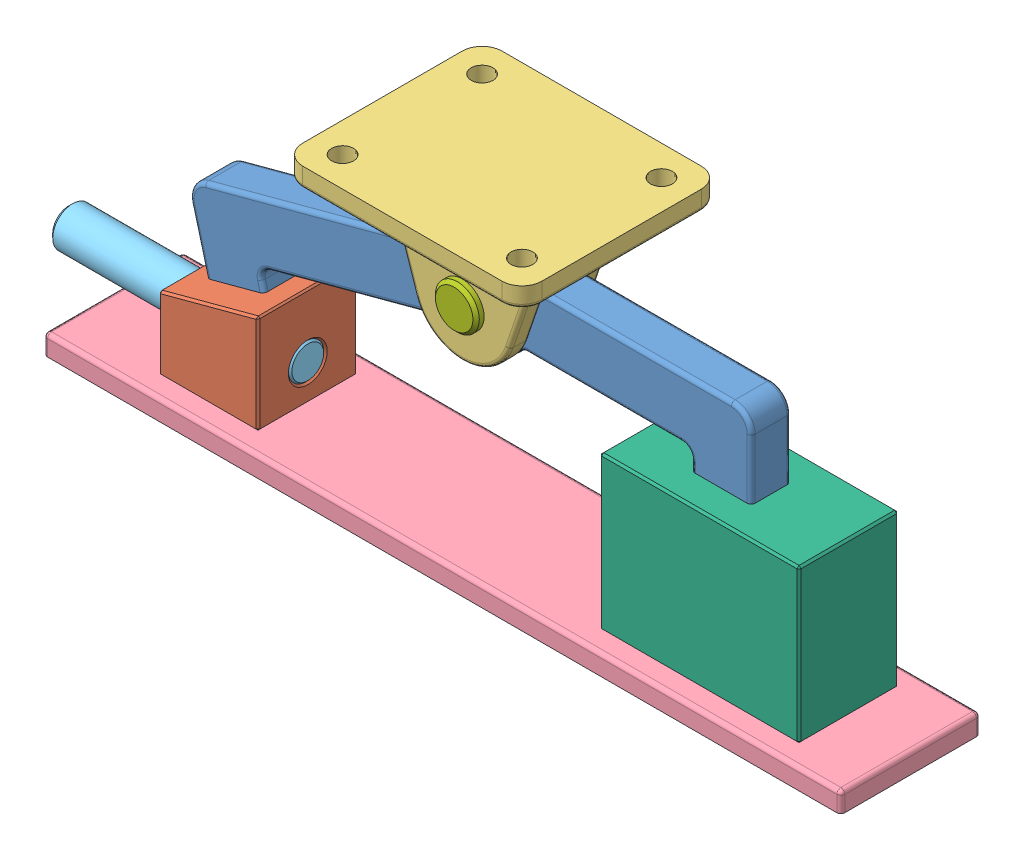
SolidWorks assembly Klemmvorrichtung, configuration Standard. Lengths in mm.
Overall size (422.47 162 100).
7 component instances, 7 part files, 19 mates.
Components (placement in the parent):
- Klemmhebel-1: Klemmhebel [Standard] at (0 105 332.9875) size (281.52 87.97 20)
- Keil-1: Keil [Standard] at (-147.4741 3 317.9875) size (50 49.79 50)
- Lagerbock-1: Lagerbock [Standard] at (0 105 352.9875) size (120 75 100)
- Gleitbahn-1: Gleitbahn [Standard] at (5 -7 342.9875) x (1 0 0) z (0 1 0) size (400 70 10)
- Zugspindel-1: Zugspindel [Standard] at (-97.4741 21 342.9875) x (0 -0.633952 0.773373) z (-1 0 0) size (20 20 120)
- Schlitten-2: Schlitten [Standard] at (124.0003 80 342.9875) x (1 0 0) z (0 -1 0) size (100 50 77)
- Clevis Pin Headed_DIN-1: Clevis Pin Headed_DIN [Clevis Pin ISO 2341 - B - 14 x 50x 4 - St] at (0 105 366.9875) x (0 0 -1) z (1 0 0) size (54 22 22)
Mates (geometry in assembly coordinates):
- Breite1: width: plane of Keil-1 through (-147.4741 3 367.9875) normal (0 0 1); plane of Keil-1 through (-147.4741 3 317.9875) normal (0 0 -1); plane of Klemmhebel-1 through (-105.9051 55.9173 332.9875) normal (0 0 -1); plane of Klemmhebel-1 through (-105.9051 55.9173 352.9875) normal (0 0 1)
- Deckungsgleich1: coincident anti-aligned: plane of Klemmhebel-1 through (-138.4184 42.029 352.9875) normal (0.258819 -0.965926 0); plane of Keil-1 through (-97.4741 53 367.9875) normal (-0.258819 0.965926 0)
- Deckungsgleich2: coincident anti-aligned: plane of Keil-1 through (-158.6702 0 367.9875) normal (0 -1 0); plane of assembly through (0 0 0) normal (0 1 0)
- Deckungsgleich7: coincident aligned: plane of Lagerbock-1 through (0 105 352.9875) normal (1 0 0); plane of assembly through (0 0 0) normal (1 0 0)
- Abstand1: distance = 155 mm aligned: plane of Lagerbock-1 through (-60 155 292.9875) normal (0 1 0); plane of assembly through (0 0 0) normal (0 1 0)
- Konzentrisch1: concentric anti-aligned: cylinder of Klemmhebel-1 through (0 105 352.9875) axis (0 0 1) radius 7; cylinder of Lagerbock-1 through (0 105 362.9875) axis (0 0 -1) radius 7
- Deckungsgleich9: coincident anti-aligned: plane of Klemmhebel-1 through (-105.9051 55.9173 352.9875) normal (0 0 1); plane of Lagerbock-1 through (0 105 352.9875) normal (0 0 -1)
- Parallel1: parallel anti-aligned: plane of Klemmhebel-1 through (105 80 352.9875) normal (0 -1 0); plane of assembly through (0 0 0) normal (0 1 0)
- Deckungsgleich11: coincident anti-aligned: plane of Keil-1 through (-147.4741 3 367.9875) normal (0 -1 0); plane of Gleitbahn-1 through (-195 3 377.9875) normal (0 1 0)
- Breite2: width: plane of Keil-1 through (-147.4741 3 367.9875) normal (0 0 1); plane of Keil-1 through (-147.4741 3 317.9875) normal (0 0 -1); plane of Gleitbahn-1 through (-195 3 307.9875) normal (0 0 -1); plane of Gleitbahn-1 through (-195 3 377.9875) normal (0 0 1)
- Abstand2: distance = 195 mm anti-aligned: plane of assembly through (0 0 0) normal (1 0 0); plane of Gleitbahn-1 through (-195 3 307.9875) normal (-1 0 0)
- Konzentrisch2: concentric anti-aligned: cylinder of Keil-1 through (-147.4741 21 342.9875) axis (-1 0 0) radius 8.75; cylinder of Zugspindel-1 through (-217.4741 21 342.9875) axis (1 0 0) radius 10
- Deckungsgleich17: coincident anti-aligned: plane of Gleitbahn-1 through (-195 3 377.9875) normal (0 1 0); plane of Schlitten-2 through (74.0003 3 317.9875) normal (0 -1 0)
- Breite4: width: plane of Gleitbahn-1 through (-195 3 377.9875) normal (0 0 1); plane of Gleitbahn-1 through (-195 3 307.9875) normal (0 0 -1); plane of Schlitten-2 through (74.0003 3 317.9875) normal (0 0 -1); plane of Schlitten-2 through (74.0003 3 367.9875) normal (0 0 1)
- Deckungsgleich18: coincident anti-aligned: plane of Klemmhebel-1 through (105 80 352.9875) normal (0 -1 0); plane of Schlitten-2 through (74.0003 80 317.9875) normal (0 1 0)
- Deckungsgleich19: coincident aligned: plane of Keil-1 through (-97.4741 3 367.9875) normal (1 0 0); plane of Zugspindel-1 through (-97.4741 21 342.9875) normal (1 0 0)
- Konzentrisch3: concentric anti-aligned: cone of Lagerbock-1 through (0 105 361.9875) axis (0 0 -1); cylinder of Clevis Pin Headed_DIN-1 through (0 105 366.9875) axis (0 0 1) radius 11
- Deckungsgleich20: coincident anti-aligned: plane of Lagerbock-1 through (0 105 362.9875) normal (0 0 1); plane of Clevis Pin Headed_DIN-1 through (0 116 362.9875) normal (0 0 -1)
- Achse2: unknown: line of Keil-1 through (-98.4741 4 367.9875) axis (0 1 0)
